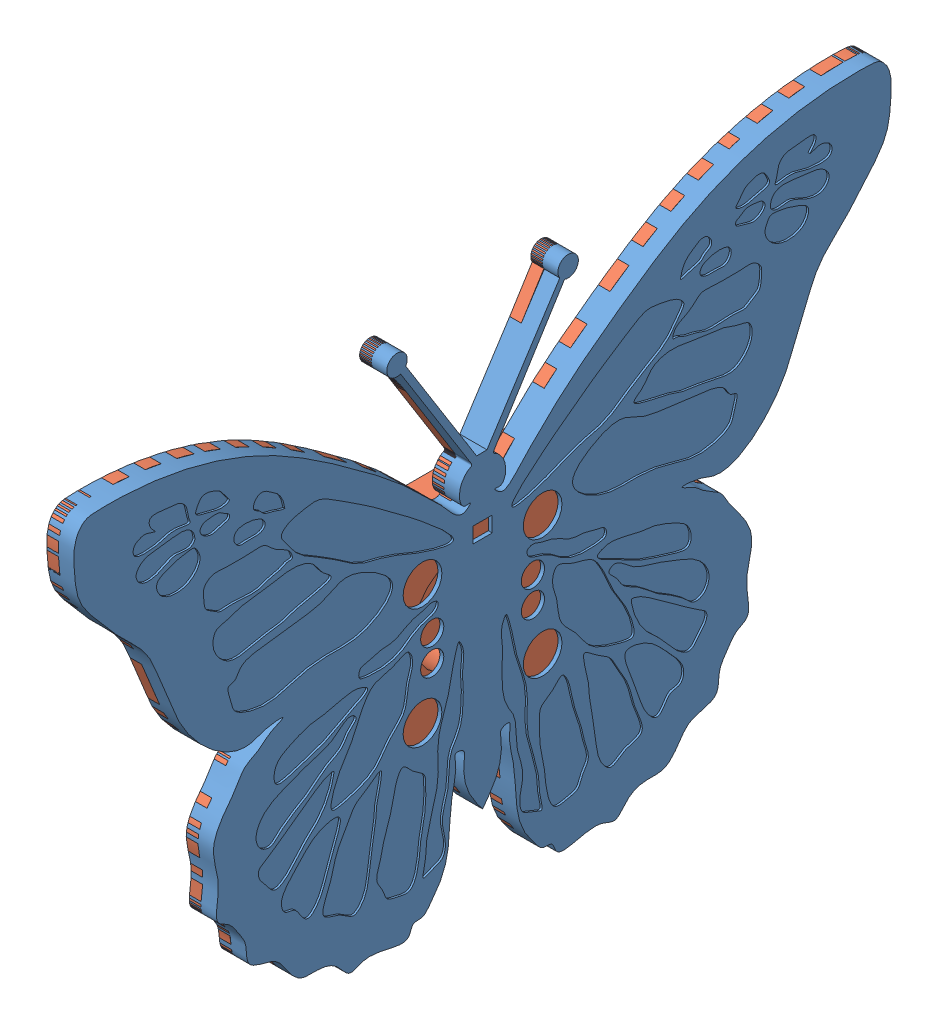
SolidWorks assembly Assem1, configuration Default. Lengths in mm.
Overall size (14 137.66 211.61).
2 component instances, 2 part files, 3 mates.
Components (placement in the parent):
- sommerfugl-2-1: sommerfugl-2 [Default] at (161.9753 121.918 73.3183) size (7 137.66 211.61)
- sommerfugl-bunn-2: sommerfugl-bunn [Default] at (164.9753 121.918 73.3183) x (-1 0 0) z (0 0 -1) size (10 137.66 211.61)
Mates (geometry in assembly coordinates):
- Parallel2: parallel: plane of sommerfugl-2-1 through (161.9753 121.918 73.3183) normal (-1 0 0); plane of sommerfugl-bunn-2 through (164.9753 122.2329 73.4915) normal (1 0 0)
- Coincident4: coincident: circle of sommerfugl-2-1; circle of sommerfugl-bunn-2
- Coincident5: coincident: circle of sommerfugl-2-1; circle of sommerfugl-bunn-2
